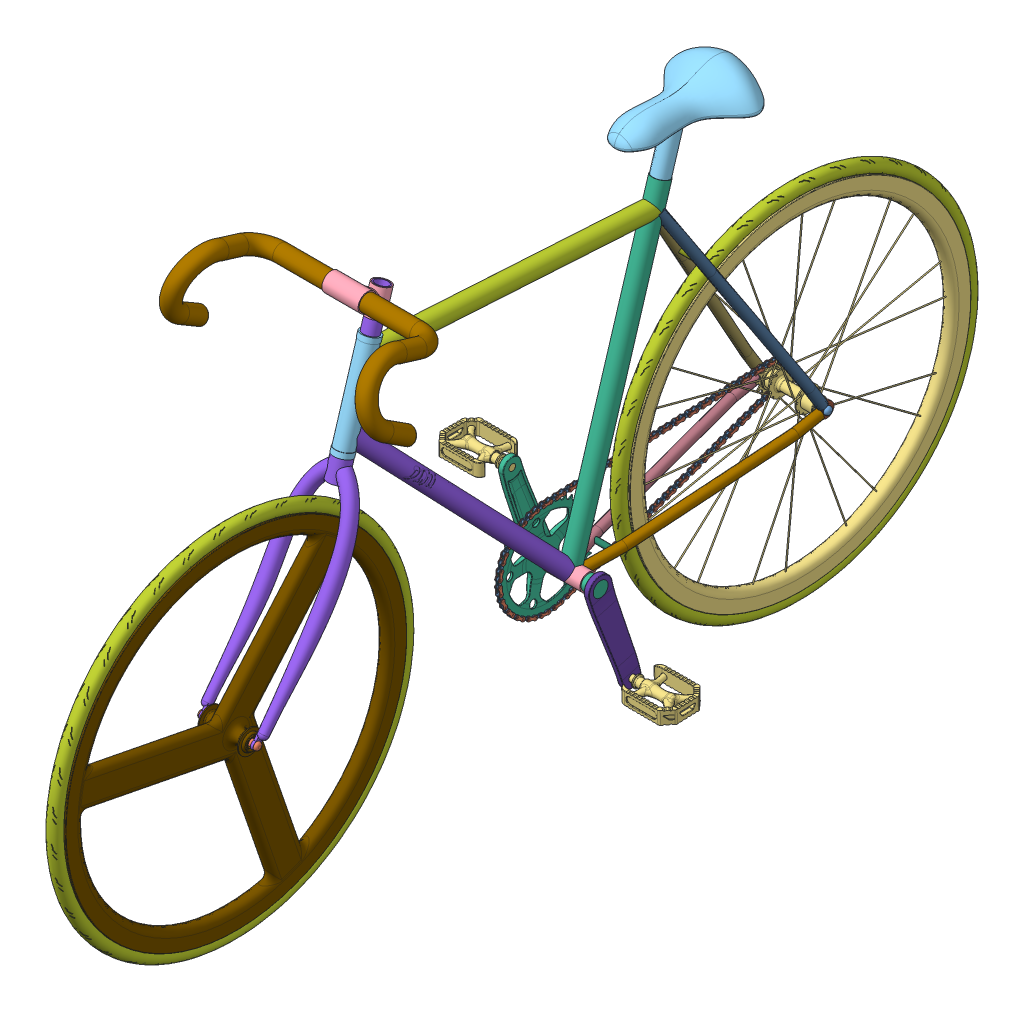
SolidWorks assembly Fixie 2, configuration Default. Lengths in mm.
Overall size (435.54 1165.89 2005.33).
126 component instances, 27 part files, 36 mates.
Components (placement in the parent):
- Axe 2-1: Axe 2 [Default] at (0 85.0139 -432.7378) x (1 0 0) z (0 0.996852 0.079286) size (142 15 15)
- Axe-1: Axe [Default] at (0 62.2338 655.6344) x (0 -0.980922 0.194402) z (1 0 0) size (15 15 115)
- Back Wheel-1: Back Wheel [Default] at (0.5 85.0139 -432.7378) x (1 0 0) z (0 0.147321 -0.989089) size (100 658.88 658.88)
- cadre-1: cadre [Défaut] at origin size (140 613.27 908.21)
  - tube pedalier^cadre-1: tube pedalier^cadre [Défaut] at origin size (73 33 33) (virtual)
  - trou pour fourche^cadre-2: trou pour fourche^cadre [Défaut] at (0 502.9172 411.5258) x (0.998411 0.016475 0.053886) z (0 -0.956305 0.292372) size (35 35 185) (virtual)
  - tube de selle^cadre-1: tube de selle^cadre [Défaut] at (0 573.7829 -175.423) x (1 0 0) z (0 0.956305 -0.292372) size (32.9 32.9 600.3) (virtual)
  - tube de tete^cadre-1: tube de tete^cadre [Défaut] at (0 561.2509 393.6914) x (1 0 0) z (0 0.060491 0.998169) size (32.9 32.9 555.16) (virtual)
  - tube du bas^cadre-3: tube du bas^cadre [Défaut] at (0 447.1547 428.5741) x (-1 0 0) z (0 -0.721947 -0.691948) size (32.91 32.9 618.4) (virtual)
  - tube arriere bas^cadre-2: tube arriere bas^cadre [Défaut] at origin size (67.83 98.35 411.57) (virtual)
  - tube arriere haut^cadre-1: tube arriere haut^cadre [Défaut] at origin size (69.56 441.01 279.99) (virtual)
  - encoche roue^cadre-7: encoche roue^cadre [Défaut] at (61 85.0139 -432.7378) x (0 -0.852467 -0.522781) z (-1 0 0) size (54 61.43 6.25) (virtual)
  - Symétrietube arriere haut^cadre-2: Symétrietube arriere haut^cadre [Défaut] x (-1 0 0) z (0 0 -1) size (69.56 441.01 279.99) (virtual)
  - Symétrietube arriere bas^cadre-3: Symétrietube arriere bas^cadre [Défaut] x (-1 0 0) z (0 0 -1) size (67.83 98.35 411.57) (virtual)
  - Symétrieencoche roue^cadre-8: Symétrieencoche roue^cadre [Défaut] at (-61 85.0139 -432.7378) x (0 -0.852467 -0.522781) z (-1 0 0) size (54 61.43 6.25) (virtual)
  - tube consolider 1^cadre-1: tube consolider 1^cadre [Défaut] x (0 0 -1) z (1 0 0) size (10 10 30.38) (virtual)
  - tube consolider 2^cadre-1: tube consolider 2^cadre [Défaut] x (0 0 -1) z (1 0 0) size (10 10 34.39) (virtual)
- Crank 2-1: Crank 2 [Default] at (65 -174.6079 -71.9344) x (0 -0.268041 0.963407) z (-1 0 0) size (45 210 26.78)
- Front Wheel-1: Front Wheel [Default] at (0 62.2338 655.6344) x (-1 0 0) z (0 0.981409 -0.191928) size (90 658.88 658.88)
- Inner Chain-1: Inner Chain [Default] at (-46 27.3912 86.5961) x (1 0 0) z (0 0.95344 -0.301582) size (5 8 20.8)
- Outter Chain-1: Outter Chain [Default] at (-46 39.2616 81.9005) x (1 0 0) z (0 0.901741 -0.432277) size (8.5 8 20.8)
- Pedal 2-1: Pedal 2 [Default] at (-136.5 163.7793 45.5671) x (0 0 1) z (1 0 0) size (80 25 117.5)
- Potence 2-1: Potence 2 [Défaut] at (0 679.4578 425.2107) x (0 -0.292372 -0.956305) z (1 0 0) size (98.9 64.61 70)
- selle-1: selle [Défaut] at (0 662.8695 -204.4368) x (-1 0 0) z (0 0.017452 -0.999848) size (178.5 284.14 238.49)
- Sprocket 2-1: Sprocket 2 [Default] at (-50 0 0) x (-1 0 0) z (0 0.783127 -0.621862) size (135 250.05 212.39)
- Tire-1: Tire [Default] at (0.5 85.0139 -432.7378) x (1 0 0) z (0 -0.268334 0.963326) size (24.5 700 700)
- Pedal 2-2: Pedal 2 [Default] at (136.5 -163.7793 -45.5671) x (0 0.031063 -0.999517) z (-1 0 0) size (80 25 117.5)
- Tire-2: Tire [Default] at (0 62.2338 655.6344) x (-1 0 0) z (0 -0.559193 -0.829038) size (24.5 700 700)
- Inner Chain-2: Inner Chain [Default] at (-46 50.3564 75.587) x (1 0 0) z (0 0.832228 -0.554433) size (5 8 20.8)
- Inner Chain-3: Inner Chain [Default] at (-46 69.3622 58.6349) x (1 0 0) z (0 0.645581 -0.763692) size (5 8 20.8)
- Inner Chain-4: Inner Chain [Default] at (-46 82.9144 37.0724) x (1 0 0) z (0 0.408175 -0.912904) size (5 8 20.8)
- Inner Chain-5: Inner Chain [Default] at (-46 89.9473 12.5952) x (1 0 0) z (0 0.138675 -0.990338) size (5 8 20.8)
- Inner Chain-6: Inner Chain [Default] at (-46 91.6836 -12.9182) x (1 0 0) z (0 0.042605 -0.999092) size (5 8 20.8)
- Inner Chain-7: Inner Chain [Default] at (-46 92.7741 -38.489) x (1 0 0) z (0 0.042605 -0.999092) size (5 8 20.8)
- Inner Chain-8: Inner Chain [Default] at (-46 93.8645 -64.0597) x (1 0 0) z (0 0.042605 -0.999092) size (5 8 20.8)
- Inner Chain-9: Inner Chain [Default] at (-46 94.9549 -89.6305) x (1 0 0) z (0 0.042605 -0.999092) size (5 8 20.8)
- Inner Chain-10: Inner Chain [Default] at (-46 96.0453 -115.2012) x (1 0 0) z (0 0.042605 -0.999092) size (5 8 20.8)
- Inner Chain-11: Inner Chain [Default] at (-46 97.1358 -140.772) x (1 0 0) z (0 0.042605 -0.999092) size (5 8 20.8)
- Inner Chain-12: Inner Chain [Default] at (-46 98.2262 -166.3428) x (1 0 0) z (0 0.042605 -0.999092) size (5 8 20.8)
- Inner Chain-13: Inner Chain [Default] at (-46 99.3166 -191.9135) x (1 0 0) z (0 0.042605 -0.999092) size (5 8 20.8)
- Inner Chain-14: Inner Chain [Default] at (-46 100.407 -217.4843) x (1 0 0) z (0 0.042605 -0.999092) size (5 8 20.8)
- Inner Chain-15: Inner Chain [Default] at (-46 101.4975 -243.055) x (1 0 0) z (0 0.042605 -0.999092) size (5 8 20.8)
- Inner Chain-16: Inner Chain [Default] at (-46 102.5879 -268.6258) x (1 0 0) z (0 0.042605 -0.999092) size (5 8 20.8)
- Inner Chain-17: Inner Chain [Default] at (-46 103.6783 -294.1966) x (1 0 0) z (0 0.042605 -0.999092) size (5 8 20.8)
- Inner Chain-18: Inner Chain [Default] at (-46 104.7687 -319.7673) x (1 0 0) z (0 0.042605 -0.999092) size (5 8 20.8)
- Inner Chain-19: Inner Chain [Default] at (-46 105.8592 -345.3381) x (1 0 0) z (0 0.042605 -0.999092) size (5 8 20.8)
- Inner Chain-20: Inner Chain [Default] at (-46 106.9496 -370.9089) x (1 0 0) z (0 0.042605 -0.999092) size (5 8 20.8)
- Inner Chain-21: Inner Chain [Default] at (-46 108.04 -396.4796) x (1 0 0) z (0 0.042605 -0.999092) size (5 8 20.8)
- Inner Chain-22: Inner Chain [Default] at (-46 109.1304 -422.0504) x (1 0 0) z (0 0.042605 -0.999092) size (5 8 20.8)
- Inner Chain-23: Inner Chain [Default] at (-46 104.3821 -446.3991) x (1 0 0) z (0 -0.576392 -0.817174) size (5 8 20.8)
- Inner Chain-24: Inner Chain [Default] at (-46 82.6898 -456.3251) x (1 0 0) z (0 -0.995181 0.098056) size (5 8 20.8)
- Inner Chain-25: Inner Chain [Default] at (-46 63.1483 -442.4511) x (1 0 0) z (0 -0.437632 0.899154) size (5 8 20.8)
- Inner Chain-26: Inner Chain [Default] at (-46 53.8499 -418.6357) x (1 0 0) z (0 -0.338529 0.940956) size (5 8 20.8)
- Inner Chain-27: Inner Chain [Default] at (-46 45.1855 -394.5529) x (1 0 0) z (0 -0.338529 0.940956) size (5 8 20.8)
- Inner Chain-28: Inner Chain [Default] at (-46 36.5212 -370.4701) x (1 0 0) z (0 -0.338529 0.940956) size (5 8 20.8)
- Inner Chain-29: Inner Chain [Default] at (-46 27.8569 -346.3872) x (1 0 0) z (0 -0.338529 0.940956) size (5 8 20.8)
- Inner Chain-30: Inner Chain [Default] at (-46 19.1926 -322.3044) x (1 0 0) z (0 -0.338529 0.940956) size (5 8 20.8)
- Inner Chain-31: Inner Chain [Default] at (-46 10.5283 -298.2216) x (1 0 0) z (0 -0.338529 0.940956) size (5 8 20.8)
- Inner Chain-32: Inner Chain [Default] at (-46 1.864 -274.1388) x (1 0 0) z (0 -0.338529 0.940956) size (5 8 20.8)
- Inner Chain-33: Inner Chain [Default] at (-46 -6.8003 -250.0559) x (1 0 0) z (0 -0.338529 0.940956) size (5 8 20.8)
- Inner Chain-34: Inner Chain [Default] at (-46 -15.4646 -225.9731) x (1 0 0) z (0 -0.338529 0.940956) size (5 8 20.8)
- Inner Chain-35: Inner Chain [Default] at (-46 -24.129 -201.8903) x (1 0 0) z (0 -0.338529 0.940956) size (5 8 20.8)
- Inner Chain-36: Inner Chain [Default] at (-46 -32.7933 -177.8074) x (1 0 0) z (0 -0.338529 0.940956) size (5 8 20.8)
- Inner Chain-37: Inner Chain [Default] at (-46 -41.4576 -153.7246) x (1 0 0) z (0 -0.338529 0.940956) size (5 8 20.8)
- Inner Chain-38: Inner Chain [Default] at (-46 -50.1219 -129.6418) x (1 0 0) z (0 -0.338529 0.940956) size (5 8 20.8)
- Inner Chain-39: Inner Chain [Default] at (-46 -58.7862 -105.559) x (1 0 0) z (0 -0.338529 0.940956) size (5 8 20.8)
- Inner Chain-40: Inner Chain [Default] at (-46 -67.4505 -81.4761) x (1 0 0) z (0 -0.338529 0.940956) size (5 8 20.8)
- Inner Chain-41: Inner Chain [Default] at (-46 -76.1148 -57.3933) x (1 0 0) z (0 -0.338529 0.940956) size (5 8 20.8)
- Inner Chain-42: Inner Chain [Default] at (-46 -84.7427 -33.2975) x (1 0 0) z (0 -0.332828 0.942988) size (5 8 20.8)
- Inner Chain-43: Inner Chain [Default] at (-46 -90.4315 -8.4441) x (1 0 0) z (0 -0.092971 0.995669) size (5 8 20.8)
- Inner Chain-44: Inner Chain [Default] at (-46 -89.2207 16.9947) x (1 0 0) z (0 0.187115 0.982338) size (5 8 20.8)
- Inner Chain-45: Inner Chain [Default] at (-46 -80.9949 41.0973) x (1 0 0) z (0 0.452489 0.89177) size (5 8 20.8)
- Inner Chain-46: Inner Chain [Default] at (-46 -66.4007 61.9686) x (1 0 0) z (0 0.682286 0.731085) size (5 8 20.8)
- Inner Chain-47: Inner Chain [Default] at (-46 -46.5858 77.9675) x (1 0 0) z (0 0.858437 0.512918) size (5 8 20.8)
- Inner Chain-48: Inner Chain [Default] at (-46 -23.1079 87.8361) x (1 0 0) z (0 0.967093 0.254423) size (5 8 20.8)
- Outter Chain-2: Outter Chain [Default] at (-46 60.4564 67.7804) x (1 0 0) z (0 0.746276 -0.665637) size (8.5 8 20.8)
- Outter Chain-3: Outter Chain [Default] at (-46 76.8978 48.331) x (1 0 0) z (0 0.532134 -0.84666) size (8.5 8 20.8)
- Outter Chain-4: Outter Chain [Default] at (-46 87.2931 25.0815) x (1 0 0) z (0 0.276153 -0.961114) size (8.5 8 20.8)
- Outter Chain-5: Outter Chain [Default] at (-46 91.1228 -0.1335) x (1 0 0) z (0 0.045039 -0.998985) size (8.5 8 20.8)
- Outter Chain-6: Outter Chain [Default] at (-46 92.2288 -25.7036) x (1 0 0) z (0 0.042605 -0.999092) size (8.5 8 20.8)
- Outter Chain-7: Outter Chain [Default] at (-46 93.3193 -51.2743) x (1 0 0) z (0 0.042605 -0.999092) size (8.5 8 20.8)
- Outter Chain-8: Outter Chain [Default] at (-46 94.4097 -76.8451) x (1 0 0) z (0 0.042605 -0.999092) size (8.5 8 20.8)
- Outter Chain-9: Outter Chain [Default] at (-46 95.5001 -102.4159) x (1 0 0) z (0 0.042605 -0.999092) size (8.5 8 20.8)
- Outter Chain-10: Outter Chain [Default] at (-46 96.5905 -127.9866) x (1 0 0) z (0 0.042605 -0.999092) size (8.5 8 20.8)
- Outter Chain-11: Outter Chain [Default] at (-46 97.681 -153.5574) x (1 0 0) z (0 0.042605 -0.999092) size (8.5 8 20.8)
- Outter Chain-12: Outter Chain [Default] at (-46 98.7714 -179.1281) x (1 0 0) z (0 0.042605 -0.999092) size (8.5 8 20.8)
- Outter Chain-13: Outter Chain [Default] at (-46 99.8618 -204.6989) x (1 0 0) z (0 0.042605 -0.999092) size (8.5 8 20.8)
- Outter Chain-14: Outter Chain [Default] at (-46 100.9522 -230.2697) x (1 0 0) z (0 0.042605 -0.999092) size (8.5 8 20.8)
- Outter Chain-15: Outter Chain [Default] at (-46 102.0427 -255.8404) x (1 0 0) z (0 0.042605 -0.999092) size (8.5 8 20.8)
- Outter Chain-16: Outter Chain [Default] at (-46 103.1331 -281.4112) x (1 0 0) z (0 0.042605 -0.999092) size (8.5 8 20.8)
- Outter Chain-17: Outter Chain [Default] at (-46 104.2235 -306.9819) x (1 0 0) z (0 0.042605 -0.999092) size (8.5 8 20.8)
- Outter Chain-18: Outter Chain [Default] at (-46 105.3139 -332.5527) x (1 0 0) z (0 0.042605 -0.999092) size (8.5 8 20.8)
- Outter Chain-19: Outter Chain [Default] at (-46 106.4044 -358.1235) x (1 0 0) z (0 0.042605 -0.999092) size (8.5 8 20.8)
- Outter Chain-20: Outter Chain [Default] at (-46 107.4948 -383.6942) x (1 0 0) z (0 0.042605 -0.999092) size (8.5 8 20.8)
- Outter Chain-21: Outter Chain [Default] at (-46 108.5852 -409.265) x (1 0 0) z (0 0.042605 -0.999092) size (8.5 8 20.8)
- Outter Chain-22: Outter Chain [Default] at (-46 108.7366 -434.8068) x (1 0 0) z (0 -0.104155 -0.994561) size (8.5 8 20.8)
- Outter Chain-23: Outter Chain [Default] at (-46 94.8758 -454.2902) x (1 0 0) z (0 -0.909325 -0.416087) size (8.5 8 20.8)
- Outter Chain-24: Outter Chain [Default] at (-46 71.1353 -451.951) x (1 0 0) z (0 -0.810632 0.585556) size (8.5 8 20.8)
- Outter Chain-25: Outter Chain [Default] at (-46 58.182 -430.6771) x (1 0 0) z (0 -0.338529 0.940956) size (8.5 8 20.8)
- Outter Chain-26: Outter Chain [Default] at (-46 49.5177 -406.5943) x (1 0 0) z (0 -0.338529 0.940956) size (8.5 8 20.8)
- Outter Chain-27: Outter Chain [Default] at (-46 40.8534 -382.5115) x (1 0 0) z (0 -0.338529 0.940956) size (8.5 8 20.8)
- Outter Chain-28: Outter Chain [Default] at (-46 32.1891 -358.4286) x (1 0 0) z (0 -0.338529 0.940956) size (8.5 8 20.8)
- Outter Chain-29: Outter Chain [Default] at (-46 23.5248 -334.3458) x (1 0 0) z (0 -0.338529 0.940956) size (8.5 8 20.8)
- Outter Chain-30: Outter Chain [Default] at (-46 14.8605 -310.263) x (1 0 0) z (0 -0.338529 0.940956) size (8.5 8 20.8)
- Outter Chain-31: Outter Chain [Default] at (-46 6.1961 -286.1802) x (1 0 0) z (0 -0.338529 0.940956) size (8.5 8 20.8)
- Outter Chain-32: Outter Chain [Default] at (-46 -2.4682 -262.0973) x (1 0 0) z (0 -0.338529 0.940956) size (8.5 8 20.8)
- Outter Chain-33: Outter Chain [Default] at (-46 -11.1325 -238.0145) x (1 0 0) z (0 -0.338529 0.940956) size (8.5 8 20.8)
- Outter Chain-34: Outter Chain [Default] at (-46 -19.7968 -213.9317) x (1 0 0) z (0 -0.338529 0.940956) size (8.5 8 20.8)
- Outter Chain-35: Outter Chain [Default] at (-46 -28.4611 -189.8489) x (1 0 0) z (0 -0.338529 0.940956) size (8.5 8 20.8)
- Outter Chain-36: Outter Chain [Default] at (-46 -37.1254 -165.766) x (1 0 0) z (0 -0.338529 0.940956) size (8.5 8 20.8)
- Outter Chain-37: Outter Chain [Default] at (-46 -45.7897 -141.6832) x (1 0 0) z (0 -0.338529 0.940956) size (8.5 8 20.8)
- Outter Chain-38: Outter Chain [Default] at (-46 -54.454 -117.6004) x (1 0 0) z (0 -0.338529 0.940956) size (8.5 8 20.8)
- Outter Chain-39: Outter Chain [Default] at (-46 -63.1184 -93.5176) x (1 0 0) z (0 -0.338529 0.940956) size (8.5 8 20.8)
- Outter Chain-40: Outter Chain [Default] at (-46 -71.7827 -69.4347) x (1 0 0) z (0 -0.338529 0.940956) size (8.5 8 20.8)
- Outter Chain-41: Outter Chain [Default] at (-46 -80.447 -45.3519) x (1 0 0) z (0 -0.338529 0.940956) size (8.5 8 20.8)
- Outter Chain-42: Outter Chain [Default] at (-46 -88.3544 -21.0393) x (1 0 0) z (0 -0.231647 0.9728) size (8.5 8 20.8)
- Outter Chain-43: Outter Chain [Default] at (-46 -90.7222 4.318) x (1 0 0) z (0 0.047542 0.998869) size (8.5 8 20.8)
- Outter Chain-44: Outter Chain [Default] at (-46 -85.9568 29.3358) x (1 0 0) z (0 0.322993 0.946401) size (8.5 8 20.8)
- Outter Chain-45: Outter Chain [Default] at (-46 -74.433 52.047) x (1 0 0) z (0 0.573048 0.819522) size (8.5 8 20.8)
- Outter Chain-46: Outter Chain [Default] at (-46 -57.0568 70.666) x (1 0 0) z (0 0.778047 0.628207) size (8.5 8 20.8)
- Outter Chain-47: Outter Chain [Default] at (-46 -35.1945 83.7288) x (1 0 0) z (0 0.921871 0.387498) size (8.5 8 20.8)
- Outter Chain-48: Outter Chain [Default] at (-46 -10.5649 90.2083) x (1 0 0) z (0 0.993212 0.116322) size (8.5 8 20.8)
- Inner Chain-49: Inner Chain [Default] at (-46 2.1868 90.7986) x (1 0 0) z (0 0.99971 -0.024077) size (5 8 20.8)
- Outter Chain-49: Outter Chain [Default] at (-46 14.8953 89.5952) x (1 0 0) z (0 0.98646 -0.164) size (8.5 8 20.8)
- fourche-2: fourche [Défaut<Brut d'usinage>] at (0 376.3038 450.2354) x (1 0 0) z (0 0.292372 0.956305) size (141.09 668.83 129.54)
- Guidon 3-1: Guidon 3 [Défaut] at (0 679.4578 425.2107) x (-1 0 0) z (0 -0.956305 0.292372) size (435.54 175.85 149.6)
Mates (geometry in assembly coordinates):
- Concentric2: concentric anti-aligned: cylinder of Pedal 2-1 through (-65 163.7793 45.5671) axis (1 0 0) radius 6.25; cylinder of Sprocket 2-1 through (127.2601 163.7793 45.5671) axis (-1 0 0) radius 6.25
- Coincident1: coincident aligned: plane of Pedal 2-1 through (-65 163.7793 39.3171) normal (1 0 0); plane of Sprocket 2-1 through (-65 150.4954 18.5166) normal (1 0 0)
- Concentric4: concentric aligned: cylinder of cadre-1/tube de selle^cadre-1 through (0 -15.78 4.8244) axis (0 0.956305 -0.292372) radius 15.55; cylinder of selle-1 through (0 438.8555 -134.1716) axis (0 0.956305 -0.292372) radius 15.55
- Coincident3: coincident aligned: plane of Crank 2-1 through (60 -20.5287 17.6431) normal (1 0 0); plane of Sprocket 2-1 through (60 0 0) normal (1 0 0)
- Parallel1: parallel anti-aligned: plane of Crank 2-1 through (73.3784 -135.0353 -14.2152) normal (0.992278 0.119496 0.033246); plane of Sprocket 2-1 through (-61.4672 33.5989 -14.0066) normal (-0.992278 -0.119496 -0.033246)
- Concentric14: concentric aligned: cylinder of Crank 2-1 through (300.6103 -163.7793 -45.5671) axis (-1 0 0) radius 6.25; cylinder of Pedal 2-2 through (65 -163.7793 -45.5671) axis (-1 0 0) radius 6.25
- Coincident6: coincident aligned: plane of Crank 2-1 through (65 -186.6698 -28.5811) normal (-1 0 0); plane of Pedal 2-2 through (65 -163.9734 -39.3201) normal (-1 0 0)
- Concentric15: concentric aligned: cylinder of cadre-1/tube de selle^cadre-1 through (0 -15.78 4.8244) axis (0 0.956305 -0.292372) radius 16.45
- Concentric16: concentric anti-aligned: cylinder of cadre-1/tube pedalier^cadre-1 through (36.5 0 0) axis (-1 0 0) radius 16.5
- Concentric18: concentric anti-aligned: circle of Back Wheel-1; circle of Tire-1
- Coincident14: coincident anti-aligned: plane of Back Wheel-1 through (9.5 85.0139 -432.7378) normal (-1 0 0); plane of Tire-1 through (9.5 400.4453 -344.8745) normal (1 0 0)
- Concentric19: concentric anti-aligned: cylinder of Axe 2-1 through (-71 85.0139 -432.7378) axis (-1 0 0) radius 6; cylinder of cadre-1/encoche roue^cadre-7 through (58.5 85.0139 -432.7378) axis (1 0 0) radius 6
- Concentric20: concentric aligned: cylinder of Axe 2-1 through (-71 85.0139 -432.7378) axis (-1 0 0) radius 6; cylinder of Back Wheel-1 through (-87.3208 85.0139 -432.7378) axis (-1 0 0) radius 9.5
- Coincident16: coincident anti-aligned: plane of Axe 2-1 through (-64.75 77.5375 -433.3324) normal (1 0 0); plane of cadre-1/Symétrieencoche roue^cadre-8 through (-64.75 85.0139 -432.7378) normal (-1 0 0)
- Width2: width aligned: plane of cadre-1/Symétrieencoche roue^cadre-8 through (-58.5 85.0139 -432.7378) normal (1 0 0); plane of cadre-1/encoche roue^cadre-7 through (58.5 85.0139 -432.7378) normal (-1 0 0); plane of Back Wheel-1 through (50 71.1666 -434.8003) normal (1 0 0); plane of Back Wheel-1 through (-50 71.1666 -434.8003) normal (-1 0 0)
- Concentric21: concentric aligned: circle of Front Wheel-1; circle of Tire-2
- Coincident18: coincident anti-aligned: plane of Front Wheel-1 through (-9 62.2338 655.6344) normal (1 0 0); plane of Tire-2 through (-9 333.6938 472.5323) normal (-1 0 0)
- Concentric23: concentric aligned: cylinder of cadre-1/tube pedalier^cadre-1 through (36.5 0 0) axis (-1 0 0) radius 14.3; cylinder of Sprocket 2-1 through (60 0 0) axis (-1 0 0) radius 14.3
- Concentric24: concentric aligned: cylinder of Crank 2-1 through (300.6103 0 0) axis (-1 0 0) radius 14.3; cylinder of Sprocket 2-1 through (60 0 0) axis (-1 0 0) radius 14.3
- Width4: width aligned: plane of cadre-1/tube pedalier^cadre-1 through (36.5 0 0) normal (1 0 0); plane of cadre-1/tube pedalier^cadre-1 through (-36.5 0 0) normal (-1 0 0); plane of Crank 2-1 through (50 -20.5287 17.6431) normal (-1 0 0); plane of Sprocket 2-1 through (-50 0 0) normal (1 0 0)
- LimitDistance1: limit distance = 98.9076 mm anti-aligned: plane of selle-1 through (0 668.3687 -204.3408) normal (0 -0.956305 0.292372); plane of cadre-1/tube de selle^cadre-1 through (0 573.7829 -175.423) normal (0 0.956305 -0.292372)
- Parallel5: parallel anti-aligned: plane of selle-1 through (0 662.8695 -204.4368) normal (-1 0 0)
- GearMate1: gear = 12 : 45 mm: circle of Sprocket 2-1; circle of Back Wheel-1
- GearMate4: gear = 179.0424 : 20.2 mm: circle of Outter Chain-1; circle of Sprocket 2-1
- Concentric26: concentric anti-aligned: cylinder of Potence 2-1 through (-35 679.4578 425.2107) axis (1 0 0) radius 15.9; cylinder of Guidon 3-1 through (0 679.4578 425.2107) axis (-1 0 0) radius 15.9
- Concentric27: concentric anti-aligned: cylinder of cadre-1/trou pour fourche^cadre-2 through (0 414.459 438.5702) axis (0 0.956305 -0.292372) radius 14.3; cylinder of fourche-2 through (0 663.6836 362.3746) axis (0 -0.956305 0.292372) radius 14.3
- Coincident20: coincident anti-aligned: plane of cadre-1/trou pour fourche^cadre-2 through (0 414.459 438.5702) normal (0 -0.956305 0.292372); plane of fourche-2 through (0.0017 427.9276 482.6241) normal (0 0.956305 -0.292372)
- Concentric28: concentric anti-aligned: cylinder of Potence 2-1 through (0 615.8684 376.9932) axis (0 0.956305 -0.292372) radius 14.3; cylinder of fourche-2 through (0 663.6836 362.3746) axis (0 -0.956305 0.292372) radius 12.084
- Coincident22: coincident aligned: plane of Potence 2-1 through (0 663.6836 362.3746) normal (0 0.956305 -0.292372); plane of fourche-2 through (0 663.6836 362.3746) normal (0 0.956305 -0.292372)
- Concentric29: concentric aligned: cylinder of Axe-1 through (57.5 62.2338 655.6344) axis (1 0 0) radius 6; cylinder of fourche-2 through (-70.543 62.2338 655.6344) axis (1 0 0) radius 6
- Coincident23: coincident anti-aligned: plane of Axe-1 through (-52.5 60.7757 648.2775) normal (1 0 0); plane of fourche-2 through (-52.5 376.3038 450.2354) normal (-1 0 0)
- Concentric30: concentric aligned: cylinder of Axe-1 through (57.5 62.2338 655.6344) axis (1 0 0) radius 6; cylinder of Front Wheel-1 through (43 62.2338 655.6344) axis (1 0 0) radius 8.5
- Width5: width aligned: plane of fourche-2 through (-47.5 376.3038 450.2354) normal (1 0 0); plane of fourche-2 through (47.5 376.3038 450.2354) normal (-1 0 0); plane of Front Wheel-1 through (39 62.2338 655.6344) normal (1 0 0); plane of Front Wheel-1 through (-39 62.2338 655.6344) normal (-1 0 0)
- ProfileCenter1: profile center = 97 mm anti-aligned: plane of Potence 2-1 through (35 679.4578 425.2107) normal (1 0 0); circle of Guidon 3-1
- Parallel6: parallel anti-aligned: plane of fourche-2 through (0 376.3038 450.2354) normal (0 0.956305 -0.292372); plane of Guidon 3-1 through (0 679.4578 425.2107) normal (0 -0.956305 0.292372)
- Parallel7: parallel anti-aligned: cylinder of fourche-2 through (47.5 62.2638 655.4642) axis (1 0 0) radius 8; cylinder of Guidon 3-1 through (0 679.4578 425.2107) axis (-1 0 0) radius 15.9
